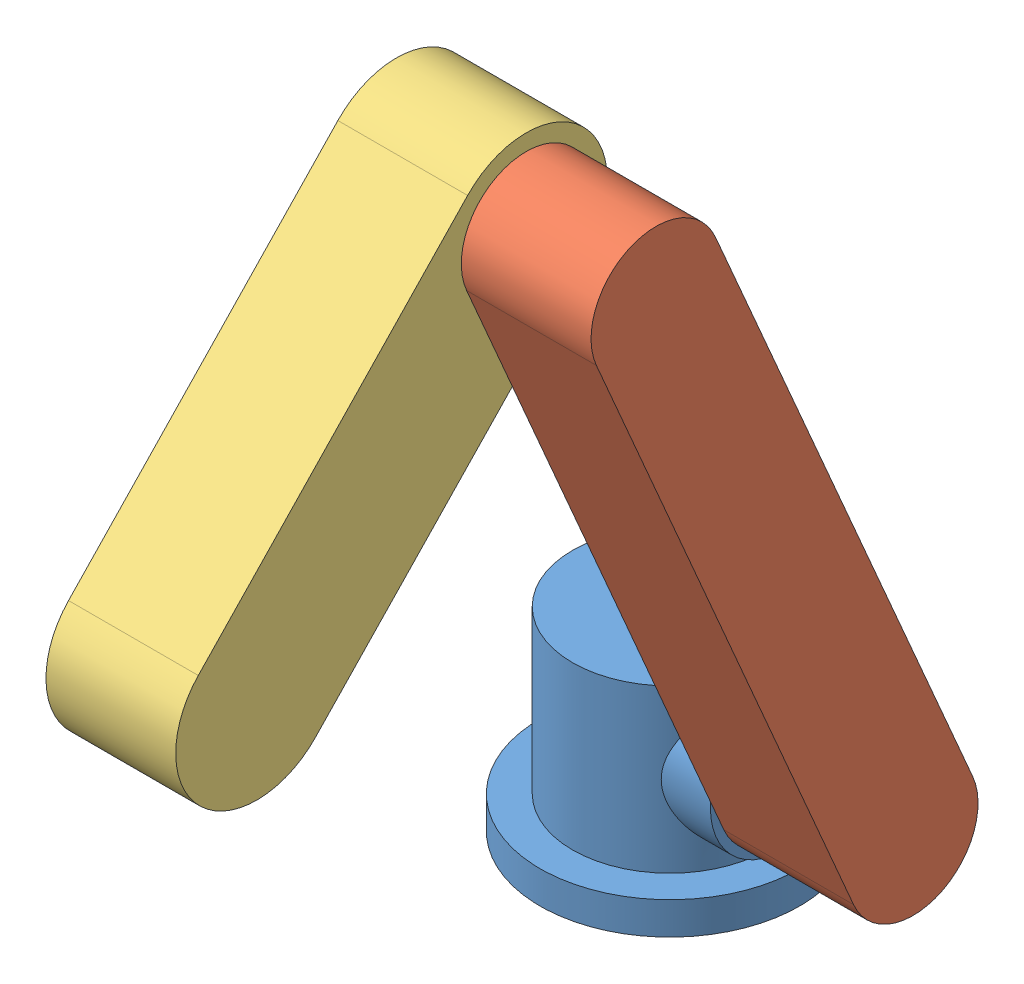
SolidWorks assembly ASM, configuration Default. Lengths in mm.
Overall size (146.05 322.53 301.84).
3 component instances, 3 part files, 5 mates.
Components (placement in the parent):
- J0-1: J0 [Default] at origin size (101.6 76.2 101.6)
- J1-1: J1 [Default] at (44.45 161.043 50.3496) x (0 -0.918055 -0.396453) z (1 0 0) size (304.8 50.8 50.8)
- J2-1: J2 [Default] at (-6.35 222.6203 153.4221) x (0 0.72199 -0.691903) z (1 0 0) size (215.9 63.5 50.8)
Mates (geometry in assembly coordinates):
- Coincident1: coordinate: unknown of J0-1
- Coincident2: coincident anti-aligned: plane of J0-1 through (44.45 44.45 0) normal (1 0 0); plane of J1-1 through (44.45 277.6359 100.6991) normal (-1 0 0)
- Concentric1: concentric aligned: cylinder of J0-1 through (44.45 44.45 0) axis (-1 0 0) radius 28.575; cylinder of J1-1 through (95.25 44.45 0) axis (-1 0 0) radius 25.4
- Concentric2: concentric aligned: cylinder of J1-1 through (95.25 277.6359 100.6991) axis (-1 0 0) radius 25.4; cylinder of J2-1 through (44.45 277.6359 100.6991) axis (-1 0 0) radius 31.75
- Coincident4: coincident anti-aligned: plane of J1-1 through (44.45 277.6359 100.6991) normal (-1 0 0); plane of J2-1 through (44.45 167.6046 206.1452) normal (1 0 0)
